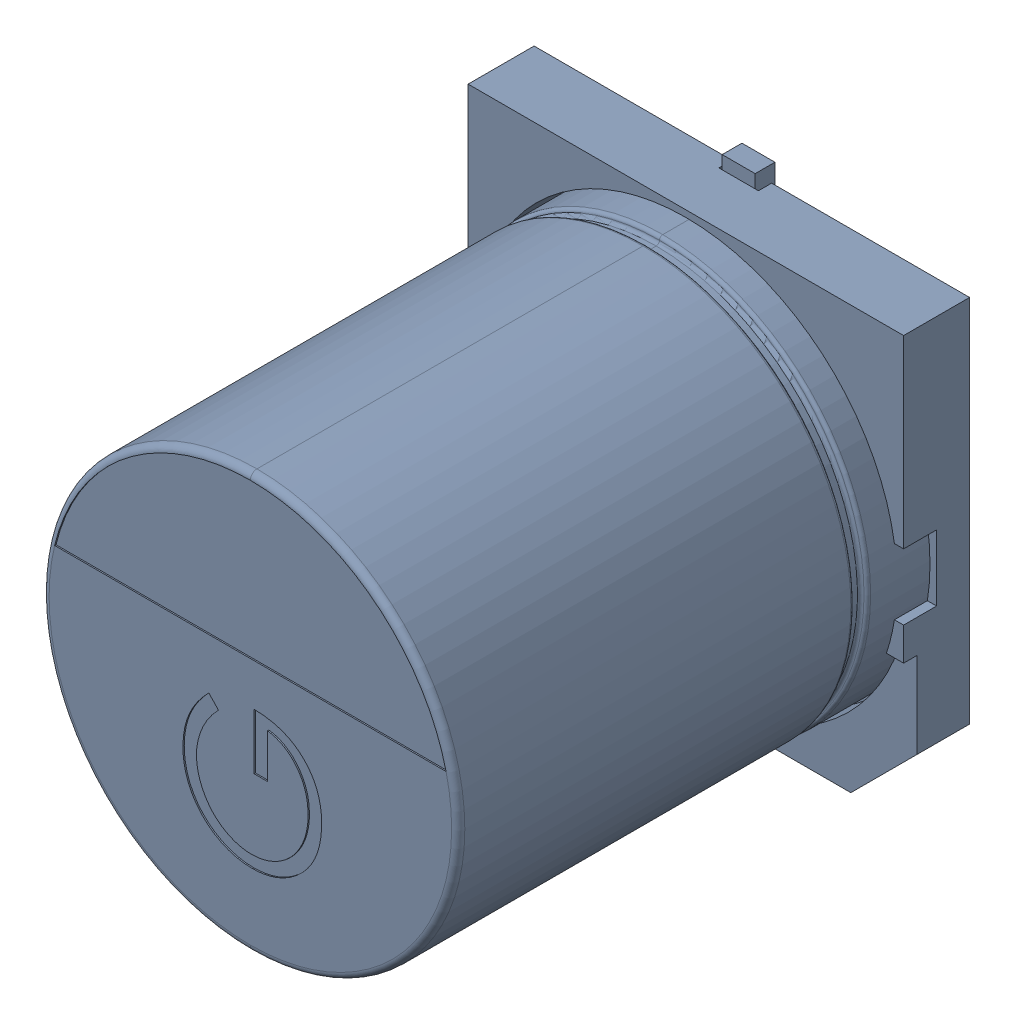
SolidWorks assembly C6, configuration 默认. Lengths in mm.
Overall size (6.6 7 7.7).
2 component instances, 1 part files, 0 mates.
Components (placement in the parent):
- SL-G-1: SL-G [默认] at (43.8149 15.4941 0) x (0 1 0) z (0 0 1) size (7 6.6 7.7)
  - SL-G-1: SL-G [默认] at origin size (7 6.6 7.7)
